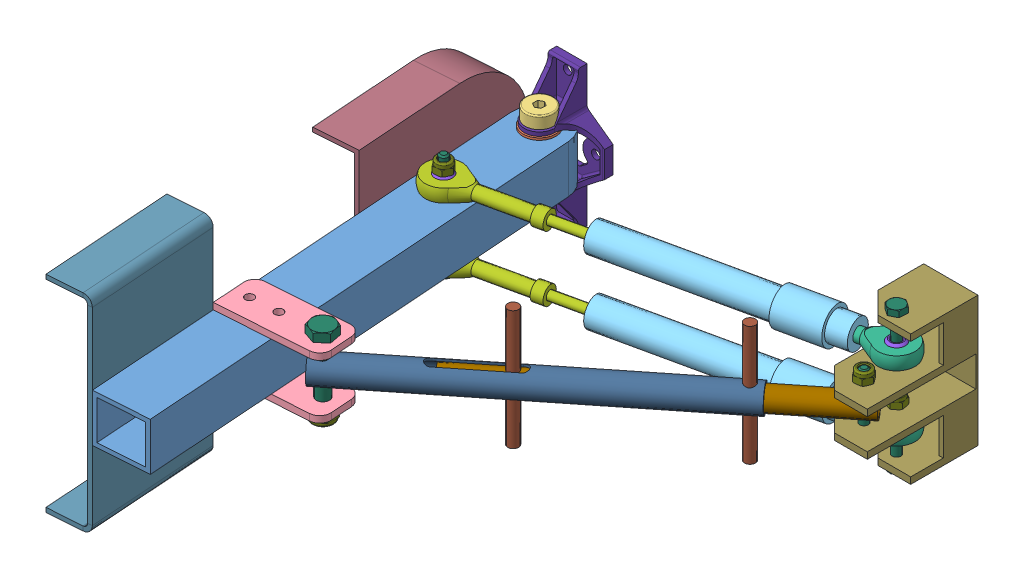
SolidWorks assembly PUTM-F-MS-PB-Acceleration_Pedal_Assembly, configuration Domyślna. Lengths in mm.
Overall size (220.08 95 224.26).
37 component instances, 17 part files, 51 mates.
Components (placement in the parent):
- PUTM-F-MS-PB-AccelerationPedal-1: PUTM-F-MS-PB-AccelerationPedal [Domyślna] at (-189.3882 -72.7325 37.8064) x (0.997564 0 -0.069756) z (0.069756 0 0.997564) size (25 22 220)
- PUTM-F-MS-PB-Bearing-1: PUTM-F-MS-PB-Bearing [Domyślna] at (-176.0467 -84.7325 49.404) x (0 -1 0) z (1 0 0) size (9.5 15 15)
- PUTM-F-MS-PB-Bearing-2: PUTM-F-MS-PB-Bearing [Domyślna] at (-176.0467 -79.7325 49.404) x (0 1 0) z (-0.718376 0 -0.695655) size (9.5 15 15)
- PUTM-FT-ELESA_ISO7379-1: PUTM-FT-ELESA_ISO7379 [8-M6-25] at (-176.0467 -62.1641 49.404) x (0 1 0) z (-0.527968 0 0.849264) size (41.5 13 13)
- PUTM-F-MS-PB-Suport2AccelerationPedal-1: PUTM-F-MS-PB-Suport2AccelerationPedal [Domyślna] at (-148.0824 -82.2325 175.2599) x (0 -1 0) z (-0.997564 0 0.069756) size (28 20 46.62)
- PUTM-F-MS-PB-Linear_sensor_RC13_Assembly-1: PUTM-F-MS-PB-Linear_sensor_RC13_Assembly [Domyślna] at (-16.2013 -97.2325 62.6043) x (0 1 0) z (0.213355 0 0.976975) size (16.1 193.22 18) (flexible)
  - PUTM-F-MS-PB-Linear_Sensor_RC13_2-1: PUTM-F-MS-PB-Linear_Sensor_RC13_2 [Domyślna] at origin size (16.1 102 16.1) (hidden)
  - PUTM-F-MS-PB-Linear_Sensor_RC13_3-1: PUTM-F-MS-PB-Linear_Sensor_RC13_3 [Domyślna] at (0 70 0) x (1 0 0) z (0 0 -1) size (7.79 24 18)
  - PUTM-F-MS-PB-Linear_Sensor_RC13-1: PUTM-F-MS-PB-Linear_Sensor_RC13 [Domyślna] at (0 74.2171 0) size (8 95 18)
  - PUTM-F-MS-PB-Linear_Sensor_RC13_4-1: PUTM-F-MS-PB-Linear_Sensor_RC13_4 [Domyślna] at (0 -15 0) x (0 0.00268 0.999996) z (-1 0 0) size (10 10 8)
  - PUTM-F-MS-PB-Linear_Sensor_RC13_4-2: PUTM-F-MS-PB-Linear_Sensor_RC13_4 [Domyślna] at (0 160.2211 0) x (0 0.000115 1) z (-1 0 0) size (10 10 8)
- PUTM-F-MS-PB-Linear_sensor_RC13_Assembly-2: PUTM-F-MS-PB-Linear_sensor_RC13_Assembly [Domyślna] at (-16.2013 -67.2325 62.6043) x (0 1 0) z (0.213355 0 0.976975) size (16.1 193.22 18) (flexible)
  - PUTM-F-MS-PB-Linear_Sensor_RC13_2-1: PUTM-F-MS-PB-Linear_Sensor_RC13_2 [Domyślna] at origin size (16.1 102 16.1)
  - PUTM-F-MS-PB-Linear_Sensor_RC13_3-1: PUTM-F-MS-PB-Linear_Sensor_RC13_3 [Domyślna] at (0 70 0) x (1 0 0) z (0 0 -1) size (7.79 24 18)
  - PUTM-F-MS-PB-Linear_Sensor_RC13-1: PUTM-F-MS-PB-Linear_Sensor_RC13 [Domyślna] at (0 74.2171 0) size (8 95 18)
  - PUTM-F-MS-PB-Linear_Sensor_RC13_4-1: PUTM-F-MS-PB-Linear_Sensor_RC13_4 [Domyślna] at (0 -15 0) x (0 0.00268 0.999996) z (-1 0 0) size (10 10 8)
  - PUTM-F-MS-PB-Linear_Sensor_RC13_4-2: PUTM-F-MS-PB-Linear_Sensor_RC13_4 [Domyślna] at (0 160.2211 0) x (0 0.000115 1) z (-1 0 0) size (10 10 8)
- PUTM-F-MS-PB-Acceleration_Stop_Assembly-1: PUTM-F-MS-PB-Acceleration_Stop_Assembly [Domyślna] at (-57.6096 -7.0771 41.6075) x (-0.622144 0 -0.782903) z (0 -1 0) size (12 187.36 55) (flexible)
  - PUTM-F-MS-PB-Stop1-1: PUTM-F-MS-PB-Stop1 [Domyślna] at (-60.5557 -116.5123 75.1554) size (10 145 10)
  - PUTM-F-MS-PB-Stop2-1: PUTM-F-MS-PB-Stop2 [Domyślna] at (-60.5557 -8.8718 75.1554) x (-1 0 0) z (0 0 1) size (12 150 12)
  - PUTM-F-MS-PB-Stop_Sleeve2-2: PUTM-F-MS-PB-Stop_Sleeve2 [Domyślna] at (-60.5557 -13.8718 72.6554) x (0 0 1) z (-0.735284 -0.677759 0) size (55 5 5)
  - PUTM-F-MS-PB-Stop_Sleeve2-3: PUTM-F-MS-PB-Stop_Sleeve2 [Domyślna] at (-60.5557 -91.5123 72.6554) x (0 0 1) z (-0.408341 -0.912829 0) size (55 5 5)
- PUTM-F-MS-PB-Suport_Acceleration_3-1: PUTM-F-MS-PB-Suport_Acceleration_3 [Domyślna] at (-14.0467 -52.2325 34.404) x (0 -1 0) z (0 0 1) size (60 25 51)
- PUTM-F-MS-PB-Footcatcher2-1: PUTM-F-MS-PB-Footcatcher2 [Domyślna] at (-186.764 -80.7325 75.3348) x (0 -1 0) z (-0.997564 0 0.069756) size (69 84.5 20)
- PUTM-F-MS-PB-Footcatcher-1: PUTM-F-MS-PB-Footcatcher [Domyślna] at (-174.0418 -129.2325 257.2705) x (0 1 0) z (-0.997564 0 0.069756) size (95 60 20)
- PUTM-FT-FABORY_DIN933-8: PUTM-FT-FABORY_DIN933 [M4x25 [01210.040.025]] at (-1.5467 -49.4325 59.404) x (0 1 0) z (-0.554074 0 0.832468) size (27.8 8.08 7)
- PUTM-FT-FABORY_DIN933-9: PUTM-FT-FABORY_DIN933 [M4x25 [01210.040.025]] at (-1.5467 -115.0325 59.404) x (0 -1 0) z (0.222877 0 -0.974847) size (27.8 8.08 7)
- PUTM-FT-FABORY_DIN933-12: PUTM-FT-FABORY_DIN933 [M4x25 [01210.040.025]] at (-1.5467 -95.0325 74.404) x (0 -1 0) z (0.222877 0 -0.974847) size (27.8 8.08 7)
- PUTM-FT-FABORY_DIN933-14: PUTM-FT-FABORY_DIN933 [M6x35 [01210.060.035]] at (-140.4019 -64.2325 184.7472) x (0 1 0) z (0.654792 0 0.755809) size (39 11.55 10)
- PUTM-FT-FABORY_DIN985-2: PUTM-FT-FABORY_DIN985 [M6 [12348.060.001]] at (-140.4019 -96.2325 184.7472) x (0.837169 0 0.546944) z (0 -1 0) size (11.9 10.35 6.18)
- PUTM-FT-FABORY_DIN985-3: PUTM-FT-FABORY_DIN985 [M4 [12348.040.001]] at (-1.5467 -89.2325 59.404) x (-0.955991 0 -0.293396) z (0 1 0) size (8.48 7.4 5.2)
- PUTM-FT-FABORY_DIN985-4: PUTM-FT-FABORY_DIN985 [M4 [12348.040.001]] at (-1.5467 -75.2325 59.404) x (-0.293396 0 -0.955991) z (0 -1 0) size (8.48 7.4 5.2)
- PUTM-FT-FABORY_DIN985-6: PUTM-FT-FABORY_DIN985 [M4 [12348.040.001]] at (-1.5467 -72.2325 74.404) x (-0.994056 0 0.108874) z (0 1 0) size (8.48 7.4 5.2)
- PUTM-FT-FABORY_DIN933-15: PUTM-FT-FABORY_DIN933 [M4x45 [01210.040.045]] at (-172.7333 -104.0325 96.7883) x (0 -1 0) z (0.222877 0 -0.974847) size (47.8 8.08 7)
- PUTM-FT-FABORY_DIN985-8: PUTM-FT-FABORY_DIN985 [M4 [12348.040.001]] at (-172.7333 -63.2325 96.7883) x (-0.994056 0 0.108874) z (0 1 0) size (8.48 7.4 5.2)
- PUTM-F-MS-PB-SuportAccelerationPedal-2: PUTM-F-MS-PB-SuportAccelerationPedal [Domyślna] at (-176.0467 -82.2325 49.404) x (0 -1 0) z (-1 0 0) size (64.67 22 26)
- PUTM-FT-FABORY_DIN985-9: PUTM-FT-FABORY_DIN985 [M6 [12348.060.001]] at (-176.0467 -96.2325 49.404) x (0.866025 0 0.5) z (0 -1 0) size (11.9 10.35 6.18)
Mates (geometry in assembly coordinates):
- Koncentryczne1: concentric anti-aligned: cylinder of PUTM-F-MS-PB-AccelerationPedal-1 through (-176.0467 -71.2325 49.404) axis (0 -1 0) radius 5; cylinder of PUTM-F-MS-PB-Bearing-1 through (-176.0467 -93.2325 49.404) axis (0 1 0) radius 5
- Wspólnie1: coincident anti-aligned: plane of PUTM-F-MS-PB-AccelerationPedal-1 through (-174.0418 -93.2325 257.2705) normal (0 -1 0); plane of PUTM-F-MS-PB-Bearing-1 through (-176.0467 -93.2325 49.404) normal (0 1 0)
- Koncentryczne2: concentric aligned: cylinder of PUTM-F-MS-PB-AccelerationPedal-1 through (-176.0467 -71.2325 49.404) axis (0 -1 0) radius 5; cylinder of PUTM-F-MS-PB-Bearing-2 through (-176.0467 -71.2325 49.404) axis (0 -1 0) radius 5
- Wspólnie2: coincident anti-aligned: plane of PUTM-F-MS-PB-AccelerationPedal-1 through (-149.1027 -71.2325 255.5266) normal (0 1 0); plane of PUTM-F-MS-PB-Bearing-2 through (-176.0467 -71.2325 49.404) normal (0 -1 0)
- Koncentryczne4: concentric aligned: cylinder of PUTM-F-MS-PB-Bearing-2 through (-176.0467 -71.2325 49.404) axis (0 -1 0) radius 4; cylinder of PUTM-FT-ELESA_ISO7379-1 through (-176.0467 -62.1641 49.404) axis (0 -1 0) radius 4
- Równolegle1: parallel anti-aligned: plane of PUTM-F-MS-PB-AccelerationPedal-1 through (-149.1027 -71.2325 255.5266) normal (0 1 0); plane of PUTM-F-MS-PB-Suport2AccelerationPedal-1 through (-131.7238 -71.2325 194.1648) normal (0 -1 0)
- Prostopadle1: perpendicular: plane of PUTM-F-MS-PB-AccelerationPedal-1 through (-174.0418 -71.2325 257.2705) normal (-0.997564 0 0.069756); plane of PUTM-F-MS-PB-Suport2AccelerationPedal-1 through (-141.6995 -96.2325 194.8624) normal (0.069756 0 0.997564)
- Wspólnie8: coincident aligned: plane of PUTM-F-MS-PB-AccelerationPedal-1 through (-174.0418 -71.2325 257.2705) normal (-0.997564 0 0.069756); plane of PUTM-F-MS-PB-Suport2AccelerationPedal-1 through (-179.2735 -96.2325 182.4532) normal (-0.997564 0 0.069756)
- Wspólnie9: coincident anti-aligned: plane of PUTM-F-MS-PB-AccelerationPedal-1 through (-174.0418 -93.2325 257.2705) normal (0 -1 0); plane of PUTM-F-MS-PB-Suport2AccelerationPedal-1 through (-131.7238 -93.2325 194.1648) normal (0 1 0)
- Odległość1: distance = 60 mm aligned: plane of PUTM-F-MS-PB-Suport2AccelerationPedal-1 through (-141.6995 -96.2325 194.8624) normal (0.069756 0 0.997564); plane of PUTM-F-MS-PB-AccelerationPedal-1 through (-174.0418 -72.7325 257.2705) normal (0.069756 0 0.997564)
- Wspólnie12: coincident anti-aligned: plane of PUTM-F-MS-PB-AccelerationPedal-1 through (-149.1027 -71.2325 255.5266) normal (0 1 0); plane of PUTM-F-MS-PB-Linear_sensor_RC13_Assembly-2/PUTM-F-MS-PB-Linear_Sensor_RC13_4-2 through (-175.7938 -71.2325 107.6917) normal (0 -1 0)
- Koncentryczne10: concentric anti-aligned: cylinder of PUTM-F-MS-PB-Acceleration_Stop_Assembly-1/PUTM-F-MS-PB-Stop1-1 through (-1.5467 -67.2325 74.404) axis (0 -1 0) radius 2.6057; cylinder of PUTM-F-MS-PB-Suport_Acceleration_3-1 through (-1.5467 -112.2325 74.404) axis (0 1 0) radius 2
- Koncentryczne11: concentric aligned: cylinder of PUTM-F-MS-PB-Linear_sensor_RC13_Assembly-1/PUTM-F-MS-PB-Linear_Sensor_RC13_4-1 through (-1.5467 -107.2325 59.404) axis (0 1 0) radius 2.5; cylinder of PUTM-F-MS-PB-Suport_Acceleration_3-1 through (-1.5467 -112.2325 59.404) axis (0 1 0) radius 2
- Koncentryczne12: concentric aligned: cylinder of PUTM-F-MS-PB-Linear_sensor_RC13_Assembly-2/PUTM-F-MS-PB-Linear_Sensor_RC13_4-1 through (-1.5467 -77.2325 59.404) axis (0 1 0) radius 2.5; cylinder of PUTM-F-MS-PB-Suport_Acceleration_3-1 through (-1.5467 -112.2325 59.404) axis (0 1 0) radius 2
- Odległość4: distance = 1 mm anti-aligned: plane of PUTM-F-MS-PB-Linear_sensor_RC13_Assembly-2/PUTM-F-MS-PB-Linear_Sensor_RC13_4-1 through (-4.6352 -71.2325 70.2995) normal (0 -1 0); plane of PUTM-F-MS-PB-Suport_Acceleration_3-1 through (-14.0467 -72.2325 85.404) normal (0 1 0)
- Równolegle5: parallel aligned: cylinder of PUTM-F-MS-PB-Linear_sensor_RC13_Assembly-1/PUTM-F-MS-PB-Linear_Sensor_RC13_2-1 through (-15.133 -97.2325 62.371) axis (0.976975 0 -0.213355) radius 6.35; cylinder of PUTM-F-MS-PB-Linear_sensor_RC13_Assembly-2/PUTM-F-MS-PB-Linear_Sensor_RC13_2-1 through (-15.133 -67.2325 62.371) axis (0.976975 0 -0.213355) radius 6.35
- Odległość5: distance = 5 mm anti-aligned: cylinder of PUTM-F-MS-PB-Acceleration_Stop_Assembly-1/PUTM-F-MS-PB-Stop2-1 through (-144.3164 -82.2325 187.858) axis (0.782903 0 -0.622144) radius 6; plane of PUTM-F-MS-PB-Suport2AccelerationPedal-1 through (-131.7238 -71.2325 194.1648) normal (0 -1 0)
- Wspólnie19: coincident anti-aligned: plane of PUTM-F-MS-PB-AccelerationPedal-1 through (-174.0418 -71.2325 257.2705) normal (-0.997564 0 0.069756); plane of PUTM-F-MS-PB-Footcatcher2-1 through (-186.764 -80.7325 75.3348) normal (0.997564 0 -0.069756)
- Odległość7: distance = 25 mm: line of PUTM-F-MS-PB-AccelerationPedal-1 through (-174.0418 -71.2325 257.2705) axis (-0.069756 0 -0.997564); line of PUTM-F-MS-PB-Footcatcher2-1 through (-186.764 -46.2325 75.3348) axis (0.069756 0 0.997564)
- Odległość8: distance = 82 mm: line of PUTM-F-MS-PB-Footcatcher2-1 through (-185.2713 -113.2325 125.3525) axis (0 1 0); line of PUTM-F-MS-PB-AccelerationPedal-1 through (-186.9942 -91.2325 43.3706) axis (0 1 0)
- Wspólnie25: coincident anti-aligned: plane of PUTM-F-MS-PB-AccelerationPedal-1 through (-174.0418 -71.2325 257.2705) normal (-0.997564 0 0.069756); plane of PUTM-F-MS-PB-Footcatcher-1 through (-174.0418 -129.2325 257.2705) normal (0.997564 0 -0.069756)
- Wspólnie26: coincident anti-aligned: line of PUTM-F-MS-PB-AccelerationPedal-1 through (-174.0418 -71.2325 257.2705) axis (0 -1 0); line of PUTM-F-MS-PB-Footcatcher-1 through (-174.0418 -125.2325 257.2705) axis (0 1 0)
- Odległość9: distance = 33 mm: line of PUTM-F-MS-PB-Footcatcher-1 through (-178.2272 -38.2325 197.4167) axis (0.069756 0 0.997564); line of PUTM-F-MS-PB-AccelerationPedal-1 through (-174.0418 -71.2325 257.2705) axis (-0.069756 0 -0.997564)
- Wspólnie27: coincident anti-aligned: plane of PUTM-F-MS-PB-AccelerationPedal-1 through (-174.0418 -93.2325 257.2705) normal (0 -1 0); plane of PUTM-F-MS-PB-Linear_sensor_RC13_Assembly-1/PUTM-F-MS-PB-Linear_Sensor_RC13_4-2 through (-175.7938 -93.2325 107.6917) normal (0 1 0)
- Koncentryczne18: concentric anti-aligned: cylinder of PUTM-F-MS-PB-Suport_Acceleration_3-1 through (-1.5467 -112.2325 59.404) axis (0 1 0) radius 2; cylinder of PUTM-FT-FABORY_DIN933-8 through (-1.5467 -77.2325 59.404) axis (0 -1 0) radius 2
- Wspólnie32: coincident anti-aligned: plane of PUTM-F-MS-PB-Suport_Acceleration_3-1 through (-14.0467 -52.2325 35.404) normal (0 1 0); plane of PUTM-FT-FABORY_DIN933-8 through (-4.4603 -52.2325 57.4647) normal (0 -1 0)
- Koncentryczne19: concentric aligned: cylinder of PUTM-F-MS-PB-Suport_Acceleration_3-1 through (-1.5467 -112.2325 59.404) axis (0 1 0) radius 2; cylinder of PUTM-FT-FABORY_DIN933-9 through (-1.5467 -87.2325 59.404) axis (0 1 0) radius 2
- Wspólnie33: coincident anti-aligned: plane of PUTM-F-MS-PB-Suport_Acceleration_3-1 through (-14.0467 -112.2325 35.404) normal (0 -1 0); plane of PUTM-FT-FABORY_DIN933-9 through (-4.9587 -112.2325 58.6239) normal (0 1 0)
- Koncentryczne20: concentric aligned: cylinder of PUTM-F-MS-PB-Suport_Acceleration_3-1 through (-1.5467 -112.2325 74.404) axis (0 1 0) radius 2; cylinder of PUTM-FT-FABORY_DIN933-12 through (-1.5467 -67.2325 74.404) axis (0 1 0) radius 2
- Wspólnie34: coincident anti-aligned: plane of PUTM-F-MS-PB-Suport_Acceleration_3-1 through (8.9533 -92.2325 85.404) normal (0 -1 0); plane of PUTM-FT-FABORY_DIN933-12 through (-4.9587 -92.2325 73.6239) normal (0 1 0)
- Wspólnie35: coincident anti-aligned: plane of PUTM-F-MS-PB-Suport2AccelerationPedal-1 through (-137.758 -68.2325 179.5501) normal (0 1 0); plane of PUTM-FT-FABORY_DIN933-14 through (-144.181 -68.2325 188.0212) normal (0 -1 0)
- Wspólnie36: coincident aligned: circle of PUTM-FT-FABORY_DIN933-14; cylinder of PUTM-FT-FABORY_DIN985-2 through (-140.4019 -100.2325 184.7472) axis (0 1 0) radius 3
- Wspólnie37: coincident anti-aligned: plane of PUTM-F-MS-PB-Suport2AccelerationPedal-1 through (-137.758 -96.2325 179.5501) normal (0 -1 0); plane of PUTM-FT-FABORY_DIN985-2 through (-140.4019 -96.2325 184.7472) normal (0 1 0)
- Koncentryczne22: concentric anti-aligned: cylinder of PUTM-FT-FABORY_DIN933-9 through (-1.5467 -87.2325 59.404) axis (0 1 0) radius 2; cylinder of PUTM-FT-FABORY_DIN985-3 through (-1.5467 -86.3325 59.404) axis (0 -1 0) radius 2
- Wspólnie38: coincident anti-aligned: plane of PUTM-F-MS-PB-Suport_Acceleration_3-1 through (-14.0467 -89.2325 85.404) normal (0 1 0); plane of PUTM-FT-FABORY_DIN985-3 through (-1.5467 -89.2325 59.404) normal (0 -1 0)
- Koncentryczne23: concentric anti-aligned: cylinder of PUTM-FT-FABORY_DIN933-8 through (-1.5467 -77.2325 59.404) axis (0 -1 0) radius 2; cylinder of PUTM-FT-FABORY_DIN985-4 through (-1.5467 -78.1325 59.404) axis (0 1 0) radius 2
- Wspólnie39: coincident anti-aligned: plane of PUTM-F-MS-PB-Suport_Acceleration_3-1 through (8.9533 -75.2325 85.404) normal (0 -1 0); plane of PUTM-FT-FABORY_DIN985-4 through (-1.5467 -75.2325 59.404) normal (0 1 0)
- Koncentryczne24: concentric anti-aligned: cylinder of PUTM-FT-FABORY_DIN933-12 through (-1.5467 -67.2325 74.404) axis (0 1 0) radius 2; cylinder of PUTM-FT-FABORY_DIN985-6 through (-1.5467 -69.3325 74.404) axis (0 -1 0) radius 2
- Wspólnie40: coincident anti-aligned: plane of PUTM-F-MS-PB-Suport_Acceleration_3-1 through (-14.0467 -72.2325 85.404) normal (0 1 0); plane of PUTM-FT-FABORY_DIN985-6 through (-1.5467 -72.2325 74.404) normal (0 -1 0)
- Wspólnie41: coincident anti-aligned: plane of PUTM-F-MS-PB-Linear_sensor_RC13_Assembly-1/PUTM-F-MS-PB-Linear_Sensor_RC13_4-2 through (-175.7938 -101.2325 107.6917) normal (0 -1 0); plane of PUTM-FT-FABORY_DIN933-15 through (-176.1452 -101.2325 96.0082) normal (0 1 0)
- Koncentryczne26: concentric anti-aligned: cylinder of PUTM-FT-FABORY_DIN933-15 through (-172.7333 -56.2325 96.7883) axis (0 1 0) radius 2; cylinder of PUTM-FT-FABORY_DIN985-8 through (-172.7333 -60.3325 96.7883) axis (0 -1 0) radius 2
- Wspólnie42: coincident anti-aligned: plane of PUTM-F-MS-PB-Linear_sensor_RC13_Assembly-2/PUTM-F-MS-PB-Linear_Sensor_RC13_4-2 through (-175.7938 -63.2325 107.6917) normal (0 1 0); plane of PUTM-FT-FABORY_DIN985-8 through (-172.7333 -63.2325 96.7883) normal (0 -1 0)
- Koncentryczne27: concentric aligned: cylinder of PUTM-F-MS-PB-Bearing-1 through (-176.0467 -93.2325 49.404) axis (0 1 0) radius 4; cylinder of PUTM-F-MS-PB-SuportAccelerationPedal-2 through (-176.0467 -96.2325 49.404) axis (0 1 0) radius 4
- Odległość11: distance = 0.25 mm anti-aligned: plane of PUTM-F-MS-PB-SuportAccelerationPedal-2 through (-169.0467 -94.4825 6.1861) normal (0 1 0); plane of PUTM-F-MS-PB-Bearing-1 through (-176.0467 -94.2325 49.404) normal (0 -1 0)
- Kąt2: planar angle = 0.069813 rad aligned: plane of PUTM-F-MS-PB-AccelerationPedal-1 through (-149.1027 -93.2325 255.5266) normal (0.997564 0 -0.069756); plane of PUTM-F-MS-PB-SuportAccelerationPedal-2 through (-169.0467 -96.2325 49.404) normal (1 0 0)
- Równolegle10: parallel anti-aligned: plane of PUTM-F-MS-PB-Suport_Acceleration_3-1 through (-14.0467 -52.2325 35.404) normal (-1 0 0); plane of PUTM-F-MS-PB-SuportAccelerationPedal-2 through (-169.0467 -96.2325 49.404) normal (1 0 0)
- Wspólnie53: coincident aligned: plane of PUTM-F-MS-PB-Suport_Acceleration_3-1 through (-14.0467 -52.2325 34.404) normal (0 0 -1); plane of PUTM-F-MS-PB-SuportAccelerationPedal-2 through (-176.0467 -96.2325 34.404) normal (0 0 -1)
- Odległość14: distance = 180 mm aligned: plane of PUTM-F-MS-PB-Suport_Acceleration_3-1 through (10.9533 -52.2325 35.404) normal (1 0 0); plane of PUTM-F-MS-PB-SuportAccelerationPedal-2 through (-169.0467 -96.2325 49.404) normal (1 0 0)
- Koncentryczne28: concentric anti-aligned: cylinder of PUTM-FT-ELESA_ISO7379-1 through (-176.0467 -62.1641 49.404) axis (0 -1 0) radius 3; cylinder of PUTM-FT-FABORY_DIN985-9 through (-176.0467 -100.2325 49.404) axis (0 1 0) radius 3
- Wspólnie56: coincident anti-aligned: plane of PUTM-F-MS-PB-SuportAccelerationPedal-2 through (-176.0467 -96.2325 49.404) normal (0 -1 0); plane of PUTM-FT-FABORY_DIN985-9 through (-176.0467 -96.2325 49.404) normal (0 1 0)
- Wspólnie57: coincident anti-aligned: plane of PUTM-F-MS-PB-SuportAccelerationPedal-2 through (-171.0467 -96.2325 6.1861) normal (-1 0 0); plane of PUTM-FT-FABORY_DIN985-9 through (-171.0467 -100.2325 46.5172) normal (1 0 0)
